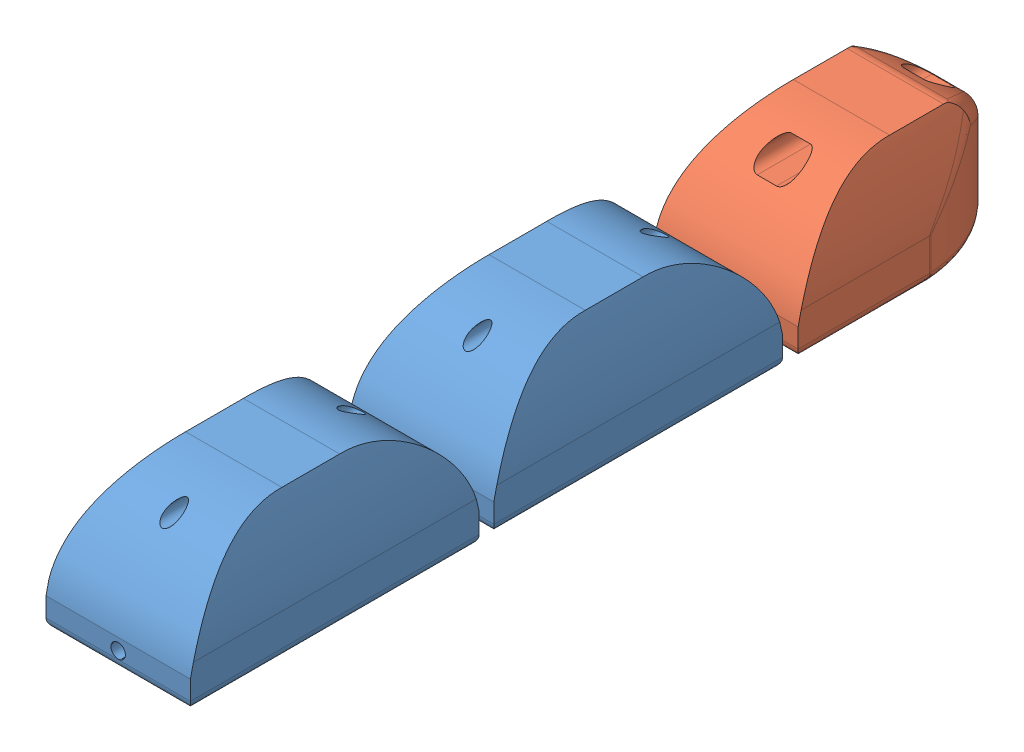
SolidWorks assembly Finger, configuration Default. Lengths in mm.
Overall size (15.2 13 87.3).
3 component instances, 2 part files, 2 mates.
Components (placement in the parent):
- Finger-1: Finger [Default] at (-11.6596 6.7393 41.1469) size (15.02 13 30)
- FingerTip-1: FingerTip [Default] at (-11.6064 6.7393 6.5903) size (15.05 13 24.05)
- Finger-2: Finger [Default] at (-11.4869 6.7393 72.8343) size (15.02 13 30)
Mates (geometry in assembly coordinates):
- Coincident1: coincident aligned: plane of Finger-1 through (3.3404 -7.8151 17.9827) normal (0 -1 0); plane of FingerTip-1 through (3.3936 -7.8151 -13.5753) normal (0 -1 0)
- Coincident2: coincident aligned: plane of Finger-1 through (3.3404 -7.8151 17.9827) normal (0 -1 0); plane of Finger-2 through (3.5131 -7.8151 49.6701) normal (0 -1 0)
